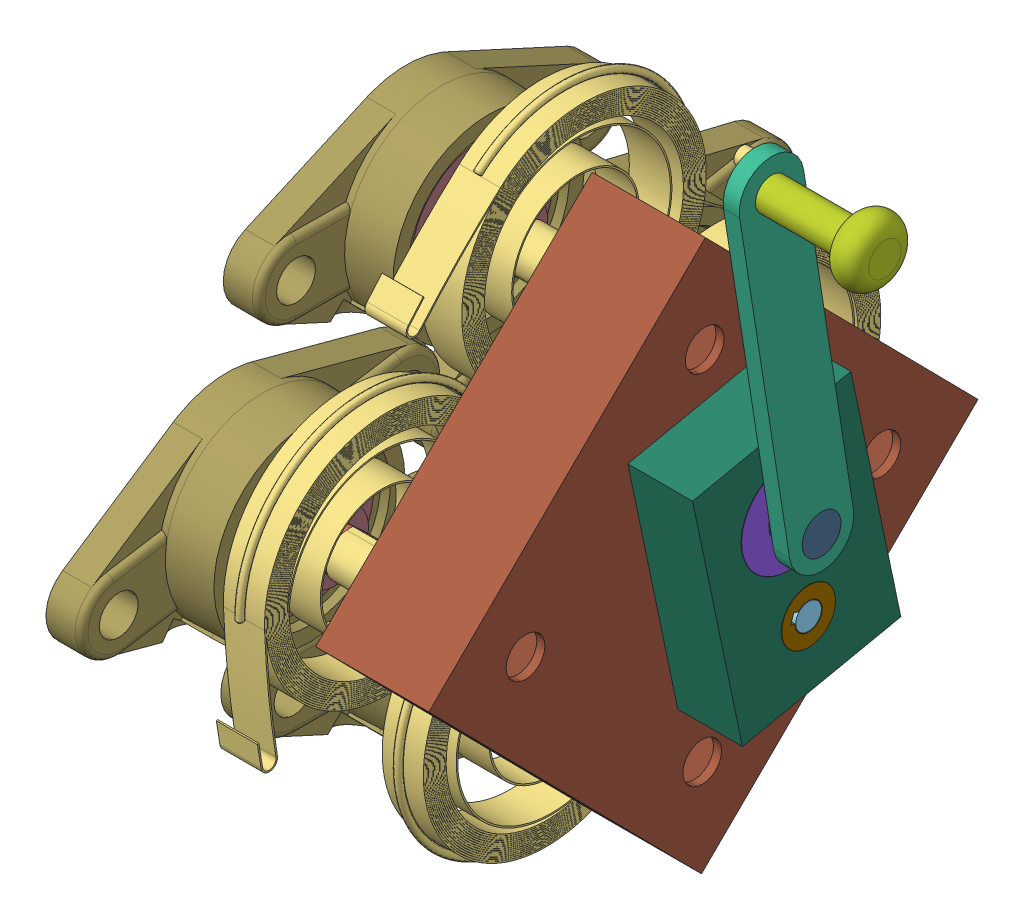
SolidWorks assembly Savassembly, configuration Default. Lengths in mm.
Overall size (169.8 255.36 232.22).
37 component instances, 15 part files, 64 mates.
Components (placement in the parent):
- KHK-US_MSGA2-15.stp-1: KHK-US_MSGA2-15.stp [Default] at (32.8346 5.5292 34.011) x (1 0 0) z (0 0.179569 -0.983745) size (30 33.73 33.9)
- small gear shaft-1: small gear shaft [Default] at (52.8346 5.5292 34.011) x (0 -0.999976 0.006982) z (0 0.006982 0.999976) size (12.4 87.5 12.4)
- 1842N11_Rotor Spring-1: 1842N11_Rotor Spring [1842N11] at (6.6846 9.9885 29.1398) x (1 0 0) z (0 0.737604 0.675233) size (12.7 78.99 81.91)
- KHK-US_MSGA2-40.stp-1: KHK-US_MSGA2-40.stp [Default] at (32.8346 -49.4694 34.395) x (1 0 0) z (0 -0.533148 -0.846022) size (30 84 84)
- large gear shaft-1: large gear shaft [Default] at (52.8346 -49.4694 34.395) x (0 -0.999976 0.006982) z (0 0.006982 0.999976) size (30 70 30)
- handbar-1: handbar [Default] at (92.8346 -19.4268 40.3968) x (0 -0.154256 0.988031) z (0 0.988031 0.154256) size (20 5 120)
- handle-1: handle [Default] at (122.8346 79.3763 55.8224) x (0 0.524924 0.851149) z (0 0.851149 -0.524924) size (20 40 20)
- small gear shaft-2: small gear shaft [Default] at (52.8346 -104.4681 34.779) x (0 -0.006982 -0.999976) z (0 -0.999976 0.006982) size (12.4 87.5 12.4)
- KHK-US_MSGA2-15.stp-2: KHK-US_MSGA2-15.stp [Default] at (32.8346 -104.4681 34.779) x (1 0 0) z (0 -0.643243 -0.765662) size (30 33.73 33.9)
- 1842N11_Rotor Spring-2: 1842N11_Rotor Spring [1842N11] at (6.6846 -107.3276 40.7318) x (1 0 0) z (0 -0.901399 -0.432989) size (12.7 78.99 81.91)
- small gear shaft-3: small gear shaft [Default] at (52.8346 -49.8534 -20.6037) x (0 -0.999976 0.006982) z (0 0.006982 0.999976) size (12.4 87.5 12.4)
- KHK-US_MSGA2-15.stp-3: KHK-US_MSGA2-15.stp [Default] at (32.8346 -49.8534 -20.6037) x (1 0 0) z (0 0.771976 0.635652) size (30 33.73 33.9)
- 1842N11_Rotor Spring-3: 1842N11_Rotor Spring [1842N11] at (6.6846 -55.0582 -24.6685) x (1 0 0) z (0 0.615515 -0.788125) size (12.7 78.99 81.91)
- small gear shaft-4: small gear shaft [Default] at (52.8346 -49.0854 89.3936) x (0 -0.006982 -0.999976) z (0 -0.999976 0.006982) size (12.4 87.5 12.4)
- KHK-US_MSGA2-15.stp-4: KHK-US_MSGA2-15.stp [Default] at (32.8346 -49.0854 89.3936) x (1 0 0) z (0 0.697271 0.716808) size (30 33.73 33.9)
- 1842N11_Rotor Spring-4: 1842N11_Rotor Spring [1842N11] at (6.6846 -42.4867 89.6584) x (1 0 0) z (0 -0.040095 0.999196) size (12.7 78.99 81.91)
- KHK-US_MSGA1-40.stp-1: KHK-US_MSGA1-40.stp [Default] at (77.8346 -19.4268 40.3968) x (1 0 0) z (0 0.998053 -0.062379) size (15 42 42)
- KHK-US_MSGA1-20.stp-1: KHK-US_MSGA1-20.stp [Default] at (77.8346 -49.4694 34.395) x (1 0 0) z (0 -0.348915 -0.937155) size (15 22 22)
- handleshaft-1: handleshaft [Default] at (97.8346 -19.4268 40.3968) x (0 -0.999976 0.006982) z (0 0.006982 0.999976) size (16 30 16)
- gearbox-1: gearbox [Default] at (20.3346 -49.4694 34.395) x (0 -0.702153 0.712027) z (0 0.712027 0.702153) size (120 35 120)
- ASKUBAL UCFL 201.stp-1: ASKUBAL UCFL 201.stp [Default] at (-36.9654 -104.4681 34.779) x (0 0.006982 0.999976) z (1 0 0) size (113 60.3 33.3)
  - _508832-b.stp-1: _508832-b.stp [Default] at origin size (113 60 25.5)
  - _508832-ir.stp-1: _508832-ir.stp [Default] at (0 0 33.3) x (0 0 -1) z (1 0 0) size (31 47 47)
  - _UCFL 200.stp-1: _UCFL 200.stp [Default] at (-21.2132 21.2132 17.5) x (0.707107 0.707107 0) z (0 0 1) size (8.09 13.8 8.1)
- ASKUBAL UCFL 201.stp-2: ASKUBAL UCFL 201.stp [Default] at (-36.9654 -49.0854 89.3936) x (0 -0.16047 0.987041) z (1 0 0) size (113 60.3 33.3)
  - _508832-b.stp-1: _508832-b.stp [Default] at origin size (113 60 25.5)
  - _508832-ir.stp-1: _508832-ir.stp [Default] at (0 0 33.3) x (0 0 -1) z (1 0 0) size (31 47 47)
  - _UCFL 200.stp-1: _UCFL 200.stp [Default] at (-21.2132 21.2132 17.5) x (0.707107 0.707107 0) z (0 0 1) size (8.09 13.8 8.1)
- ASKUBAL UCFL 201.stp-3: ASKUBAL UCFL 201.stp [Default] at (-36.9654 -49.8534 -20.6037) x (0 0.185583 -0.982629) z (1 0 0) size (113 60.3 33.3)
  - _508832-b.stp-1: _508832-b.stp [Default] at origin size (113 60 25.5)
  - _508832-ir.stp-1: _508832-ir.stp [Default] at (0 0 33.3) x (0 0 -1) z (1 0 0) size (31 47 47)
  - _UCFL 200.stp-1: _UCFL 200.stp [Default] at (-21.2132 21.2132 17.5) x (0.707107 0.707107 0) z (0 0 1) size (8.09 13.8 8.1)
- ASKUBAL UCFL 201.stp-4: ASKUBAL UCFL 201.stp [Default] at (-36.9654 5.5292 34.011) x (0 0.006982 0.999976) z (1 0 0) size (113 60.3 33.3)
  - _508832-b.stp-1: _508832-b.stp [Default] at origin size (113 60 25.5)
  - _508832-ir.stp-1: _508832-ir.stp [Default] at (0 0 33.3) x (0 0 -1) z (1 0 0) size (31 47 47)
  - _UCFL 200.stp-1: _UCFL 200.stp [Default] at (-21.2132 21.2132 17.5) x (0.707107 0.707107 0) z (0 0 1) size (8.09 13.8 8.1)
- smallgearbox-1: smallgearbox [Default] at (87.7472 -20.1105 40.5639) x (0 -0.20563 0.97863) z (0 -0.97863 -0.20563) size (50 20 75)
Mates (geometry in assembly coordinates):
- Parallel1: parallel aligned: plane of KHK-US_MSGA2-15.stp-1 through (52.8346 5.5292 34.011) normal (1 0 0)
- Concentric1: concentric aligned: cylinder of KHK-US_MSGA2-15.stp-1 through (44.8346 5.5292 34.011) axis (1 0 0) radius 6; cylinder of small gear shaft-1 through (52.8346 5.5292 34.011) axis (1 0 0) radius 6
- Coincident1: coincident aligned: plane of KHK-US_MSGA2-15.stp-1 through (52.8346 5.5292 34.011) normal (1 0 0); plane of small gear shaft-1 through (52.8346 5.5292 34.011) normal (1 0 0)
- Concentric2: concentric aligned: cylinder of small gear shaft-1 through (52.8346 5.5292 34.011) axis (1 0 0) radius 6.2; cylinder of 1842N11_Rotor Spring-1 through (6.6846 5.5292 34.011) axis (1 0 0) radius 6.1504
- Tangent1: tangent: plane of small gear shaft-1 through (0.3346 -0.4706 34.0529) normal (-1 0 0); curve of 1842N11_Rotor Spring-1
- Coincident2: coincident aligned: plane of KHK-US_MSGA2-15.stp-1 through (42.8346 5.5292 34.011) normal (1 0 0); plane of KHK-US_MSGA2-40.stp-1 through (42.8346 -49.4694 34.395) normal (1 0 0)
- GearMate1: gear = 34 : 84 mm: cylinder of KHK-US_MSGA2-40.stp-1 through (42.8346 -49.4694 34.395) axis (1 0 0) radius 42; cylinder of KHK-US_MSGA2-15.stp-1 through (42.8346 5.5292 34.011) axis (1 0 0) radius 17
- Concentric3: concentric anti-aligned: cylinder of KHK-US_MSGA2-40.stp-1 through (44.8346 -49.4694 34.395) axis (1 0 0) radius 10; cylinder of large gear shaft-1 through (52.8346 -49.4694 34.395) axis (-1 0 0) radius 10
- Coincident3: coincident anti-aligned: plane of KHK-US_MSGA2-40.stp-1 through (22.8346 -49.4694 34.395) normal (-1 0 0); plane of large gear shaft-1 through (22.8346 -38.4697 34.3182) normal (1 0 0)
- Coincident4: coincident aligned: plane of small gear shaft-1 through (52.8346 5.5292 34.011) normal (0 0.006982 0.999976); plane of large gear shaft-1 through (52.8346 -49.4694 34.395) normal (0 0.006982 0.999976)
- Concentric5: concentric anti-aligned: cylinder of handbar-1 through (97.8346 79.3763 55.8224) axis (-1 0 0) radius 5; cylinder of handle-1 through (122.8346 79.3763 55.8224) axis (1 0 0) radius 5
- Coincident6: coincident aligned: plane of handbar-1 through (92.8346 -19.4268 40.3968) normal (-1 0 0); plane of handle-1 through (92.8346 79.3763 55.8224) normal (-1 0 0)
- Coincident7: coincident anti-aligned: plane of small gear shaft-1 through (52.8346 5.5292 34.011) normal (0 0.006982 0.999976); plane of small gear shaft-2 through (52.8346 -104.4681 34.779) normal (0 -0.006982 -0.999976)
- Coincident8: coincident aligned: plane of small gear shaft-1 through (52.8346 5.5292 34.011) normal (1 0 0); plane of small gear shaft-2 through (52.8346 -104.4681 34.779) normal (1 0 0)
- Coincident9: coincident aligned: plane of small gear shaft-2 through (52.8346 -104.4681 34.779) normal (1 0 0); plane of KHK-US_MSGA2-15.stp-2 through (52.8346 -104.4681 34.779) normal (1 0 0)
- Concentric6: concentric aligned: cylinder of small gear shaft-2 through (52.8346 -104.4681 34.779) axis (1 0 0) radius 6; cylinder of KHK-US_MSGA2-15.stp-2 through (44.8346 -104.4681 34.779) axis (1 0 0) radius 6
- GearMate2: gear = 34 : 84 mm: cylinder of KHK-US_MSGA2-40.stp-1 through (42.8346 -49.4694 34.395) axis (1 0 0) radius 42; cylinder of KHK-US_MSGA2-15.stp-2 through (42.8346 -104.4681 34.779) axis (1 0 0) radius 17
- Concentric7: concentric aligned: cylinder of small gear shaft-2 through (52.8346 -104.4681 34.779) axis (1 0 0) radius 6.2; cylinder of 1842N11_Rotor Spring-2 through (6.6846 -104.4681 34.779) axis (1 0 0) radius 6.1504
- Coincident10: coincident aligned: plane of small gear shaft-2 through (0.3346 -104.51 28.7791) normal (-1 0 0); plane of 1842N11_Rotor Spring-2 through (0.3346 -138.0529 25.9717) normal (-1 0 0)
- Coincident11: coincident aligned: plane of large gear shaft-1 through (52.8346 -49.4694 34.395) normal (0 -0.999976 0.006982); plane of small gear shaft-3 through (52.8346 -49.8534 -20.6037) normal (0 -0.999976 0.006982)
- Coincident12: coincident aligned: plane of small gear shaft-1 through (52.8346 5.5292 34.011) normal (1 0 0); plane of small gear shaft-3 through (52.8346 -49.8534 -20.6037) normal (1 0 0)
- Concentric8: concentric aligned: cylinder of small gear shaft-3 through (52.8346 -49.8534 -20.6037) axis (1 0 0) radius 6.2; cylinder of KHK-US_MSGA2-15.stp-3 through (44.8346 -49.8534 -20.6037) axis (1 0 0) radius 6
- Coincident14: coincident aligned: plane of small gear shaft-3 through (52.8346 -49.8534 -20.6037) normal (1 0 0); plane of KHK-US_MSGA2-15.stp-3 through (52.8346 -49.8534 -20.6037) normal (1 0 0)
- GearMate3: gear = 84 : 34 mm: cylinder of KHK-US_MSGA2-15.stp-3 through (42.8346 -49.8534 -20.6037) axis (1 0 0) radius 17; cylinder of KHK-US_MSGA2-40.stp-1 through (42.8346 -49.4694 34.395) axis (1 0 0) radius 42
- Concentric9: concentric aligned: cylinder of small gear shaft-3 through (52.8346 -49.8534 -20.6037) axis (1 0 0) radius 6.2; cylinder of 1842N11_Rotor Spring-3 through (6.6846 -49.8534 -20.6037) axis (1 0 0) radius 6.1504
- Coincident15: coincident aligned: plane of small gear shaft-3 through (0.3346 -55.8533 -20.5618) normal (-1 0 0); plane of 1842N11_Rotor Spring-3 through (0.3346 -34.0764 -51.5326) normal (-1 0 0)
- Coincident16: coincident aligned: plane of small gear shaft-3 through (52.8346 -49.8534 -20.6037) normal (0 -0.999976 0.006982); plane of small gear shaft-4 through (52.8346 -49.0854 89.3936) normal (0 -0.999976 0.006982)
- Coincident17: coincident aligned: plane of small gear shaft-3 through (52.8346 -49.8534 -20.6037) normal (1 0 0); plane of small gear shaft-4 through (52.8346 -49.0854 89.3936) normal (1 0 0)
- Concentric10: concentric aligned: cylinder of small gear shaft-4 through (52.8346 -49.0854 89.3936) axis (1 0 0) radius 6; cylinder of KHK-US_MSGA2-15.stp-4 through (44.8346 -49.0854 89.3936) axis (1 0 0) radius 6
- Coincident18: coincident aligned: plane of KHK-US_MSGA2-15.stp-1 through (52.8346 5.5292 34.011) normal (1 0 0); plane of KHK-US_MSGA2-15.stp-4 through (52.8346 -49.0854 89.3936) normal (1 0 0)
- GearMate4: gear = 84 : 34 mm: cylinder of KHK-US_MSGA2-15.stp-4 through (42.8346 -49.0854 89.3936) axis (1 0 0) radius 17; cylinder of KHK-US_MSGA2-40.stp-1 through (42.8346 -49.4694 34.395) axis (1 0 0) radius 42
- Concentric12: concentric aligned: cylinder of small gear shaft-4 through (52.8346 -49.0854 89.3936) axis (1 0 0) radius 6.2; cylinder of 1842N11_Rotor Spring-4 through (6.6846 -49.0854 89.3936) axis (1 0 0) radius 6.1504
- Coincident19: coincident aligned: plane of small gear shaft-4 through (0.3346 -49.1273 83.3938) normal (-1 0 0); plane of 1842N11_Rotor Spring-4 through (0.3346 -43.8545 123.7178) normal (-1 0 0)
- Coincident20: coincident aligned: plane of small gear shaft-2 through (52.8346 -104.4681 34.779) normal (0 -0.999976 0.006982)
- Coincident22: coincident aligned: plane of small gear shaft-1 through (52.8346 5.5292 34.011) normal (0 -0.999976 0.006982)
- Coincident24: coincident anti-aligned: plane of small gear shaft-4 through (52.8346 -49.0854 89.3936) normal (0 -0.006982 -0.999976)
- Coincident25: coincident aligned: plane of small gear shaft-3 through (52.8346 -49.8534 -20.6037) normal (0 0.006982 0.999976)
- Coincident26: coincident aligned: plane of large gear shaft-1 through (87.8346 -49.4694 34.395) normal (1 0 0); plane of KHK-US_MSGA1-40.stp-1 through (87.8346 -19.4268 40.3968) normal (1 0 0)
- Coincident27: coincident aligned: plane of KHK-US_MSGA1-40.stp-1 through (87.8346 -19.4268 40.3968) normal (1 0 0); plane of KHK-US_MSGA1-20.stp-1 through (87.8346 -49.4694 34.395) normal (1 0 0)
- GearMate5: gear = 22 : 42 mm: cylinder of KHK-US_MSGA1-40.stp-1 through (82.8346 -19.4268 40.3968) axis (1 0 0) radius 21; cylinder of KHK-US_MSGA1-20.stp-1 through (82.8346 -49.4694 34.395) axis (1 0 0) radius 11
- Coincident29: coincident aligned: plane of handleshaft-1 through (97.8346 -19.4268 40.3968) normal (0 -0.999976 0.006982)
- Concentric15: concentric anti-aligned: cylinder of handbar-1 through (97.8346 -19.4268 40.3968) axis (-1 0 0) radius 6; cylinder of handleshaft-1 through (97.8346 -19.4268 40.3968) axis (1 0 0) radius 6
- Coincident31: coincident aligned: plane of handbar-1 through (97.8346 -19.4268 40.3968) normal (1 0 0); plane of handleshaft-1 through (97.8346 -19.4268 40.3968) normal (1 0 0)
- Concentric16: concentric anti-aligned: cylinder of large gear shaft-1 through (52.8346 -49.4694 34.395) axis (-1 0 0) radius 4; cylinder of KHK-US_MSGA1-20.stp-1 through (83.8346 -49.4694 34.395) axis (1 0 0) radius 4
- Coincident32: coincident aligned: plane of large gear shaft-1 through (87.8346 -49.4694 34.395) normal (1 0 0); plane of KHK-US_MSGA1-20.stp-1 through (87.8346 -49.4694 34.395) normal (1 0 0)
- Coincident33: coincident anti-aligned: plane of KHK-US_MSGA1-40.stp-1 through (72.8346 -19.4268 40.3968) normal (-1 0 0); plane of handleshaft-1 through (72.8346 -26.4266 40.4457) normal (1 0 0)
- Coincident34: coincident anti-aligned: plane of KHK-US_MSGA1-40.stp-1 through (72.8346 -19.4268 40.3968) normal (-1 0 0); plane of handleshaft-1 through (72.8346 -26.4266 40.4457) normal (1 0 0)
- Concentric17: concentric aligned: cylinder of KHK-US_MSGA1-40.stp-1 through (83.8346 -19.4268 40.3968) axis (1 0 0) radius 6; cylinder of handleshaft-1 through (97.8346 -19.4268 40.3968) axis (1 0 0) radius 6
- Coincident35: coincident aligned: plane of handleshaft-1 through (97.8346 -19.4268 40.3968) normal (0 -0.999976 0.006982)
- GearMate7: gear = 84 : 22 mm: cylinder of KHK-US_MSGA1-20.stp-1 through (82.8346 -49.4694 34.395) axis (1 0 0) radius 11; cylinder of KHK-US_MSGA2-40.stp-1 through (42.8346 -49.4694 34.395) axis (1 0 0) radius 42
- Concentric18: concentric aligned: cylinder of large gear shaft-1 through (52.8346 -49.4694 34.395) axis (-1 0 0) radius 8; cylinder of gearbox-1 through (55.3346 -49.4694 34.395) axis (-1 0 0) radius 8
- Concentric19: concentric anti-aligned: cylinder of small gear shaft-2 through (52.8346 -104.4681 34.779) axis (1 0 0) radius 6.2; cylinder of gearbox-1 through (55.3346 -104.4681 34.779) axis (-1 0 0) radius 6
- Coincident37: coincident anti-aligned: plane of small gear shaft-2 through (20.3346 -104.51 28.7791) normal (1 0 0); plane of gearbox-1 through (20.3346 -49.4694 34.395) normal (-1 0 0)
- Concentric20: concentric aligned: cylinder of small gear shaft-2 through (52.8346 -104.4681 34.779) axis (1 0 0) radius 6; cylinder of ASKUBAL UCFL 201.stp-1/_508832-ir.stp-1 through (-34.6654 -104.4681 34.779) axis (1 0 0) radius 6
- Coincident38: coincident aligned: plane of small gear shaft-2 through (-34.6654 -104.4681 34.779) normal (-1 0 0); plane of ASKUBAL UCFL 201.stp-1/_508832-ir.stp-1 through (-34.6654 -110.468 34.8209) normal (-1 0 0)
- Coincident39: coincident aligned: plane of small gear shaft-2 through (52.8346 -104.4681 34.779) normal (0 -0.999976 0.006982); plane of ASKUBAL UCFL 201.stp-1 through (-36.9654 -104.4681 34.779) normal (0 -0.999976 0.006982)
- Concentric21: concentric aligned: cylinder of small gear shaft-4 through (52.8346 -49.0854 89.3936) axis (1 0 0) radius 6; cylinder of ASKUBAL UCFL 201.stp-2/_508832-ir.stp-1 through (-34.6654 -49.0854 89.3936) axis (1 0 0) radius 6
- Coincident40: coincident aligned: plane of small gear shaft-4 through (-34.6654 -49.0854 89.3936) normal (-1 0 0); plane of ASKUBAL UCFL 201.stp-2/_508832-ir.stp-1 through (-34.6654 -55.0077 88.4308) normal (-1 0 0)
- Concentric23: concentric aligned: cylinder of small gear shaft-3 through (52.8346 -49.8534 -20.6037) axis (1 0 0) radius 6; cylinder of ASKUBAL UCFL 201.stp-3/_508832-ir.stp-1 through (-34.6654 -49.8534 -20.6037) axis (1 0 0) radius 6
- Coincident42: coincident aligned: plane of small gear shaft-3 through (-34.6654 -49.8534 -20.6037) normal (-1 0 0); plane of ASKUBAL UCFL 201.stp-3/_508832-ir.stp-1 through (-34.6654 -43.9577 -19.4902) normal (-1 0 0)
- Coincident44: coincident anti-aligned: circle of small gear shaft-1; circle of ASKUBAL UCFL 201.stp-4/_508832-ir.stp-1
- Coincident45: coincident aligned: plane of small gear shaft-1 through (-34.6654 5.5292 34.011) normal (-1 0 0); plane of ASKUBAL UCFL 201.stp-4/_508832-ir.stp-1 through (-34.6654 -0.4706 34.0529) normal (-1 0 0)
- Parallel2: parallel aligned: plane of ASKUBAL UCFL 201.stp-1 through (-36.9654 -104.4681 34.779) normal (0 -0.999976 0.006982); plane of ASKUBAL UCFL 201.stp-4 through (-36.9654 5.5292 34.011) normal (0 -0.999976 0.006982)
- Concentric24: concentric anti-aligned: cylinder of large gear shaft-1 through (52.8346 -49.4694 34.395) axis (-1 0 0) radius 8; cylinder of smallgearbox-1 through (67.7472 -49.4694 34.395) axis (1 0 0) radius 8
